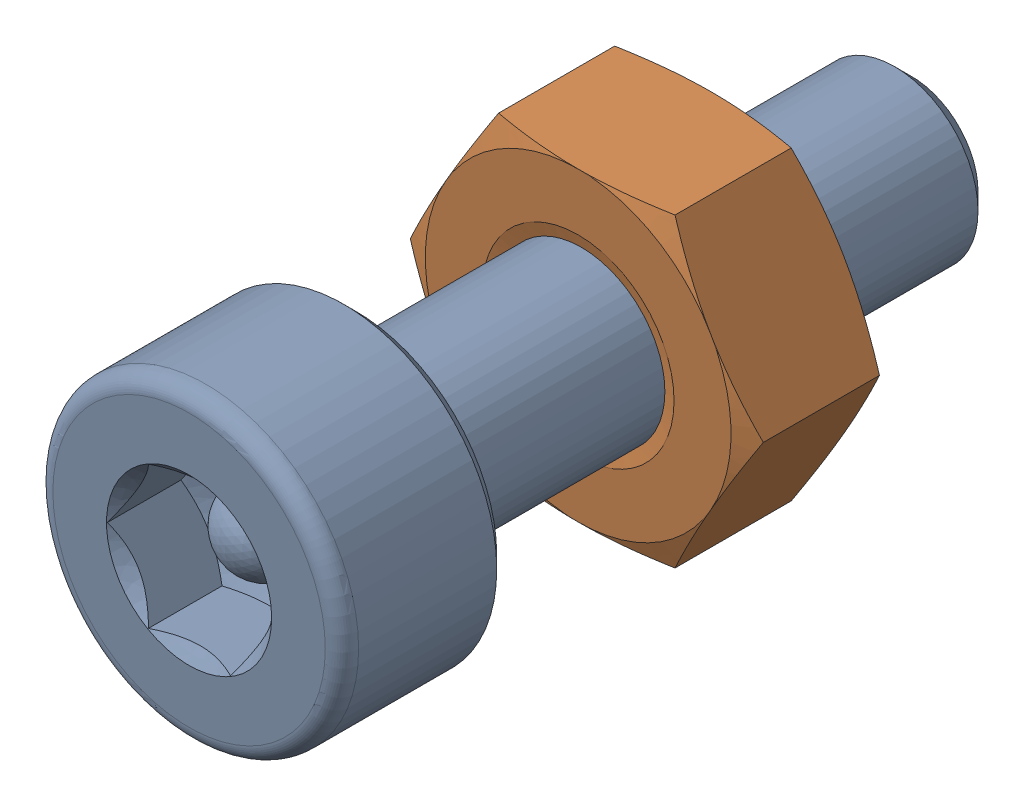
SolidWorks assembly Screw and Nut M3x010_020-1, configuration Varsayılan. Lengths in mm.
Overall size (6.35 5.5 13.14).
2 component instances, 2 part files, 0 mates.
Components (placement in the parent):
- M3x10-Screw019-1-1: M3x10-Screw019-1 [Varsayılan] at origin size (5.5 5.5 13.14)
- M3-Nut051-1-1: M3-Nut051-1 [Varsayılan] at (0 0 -4) x (-1 0 0) z (0 0 -1) size (6.35 5.5 2.4)
